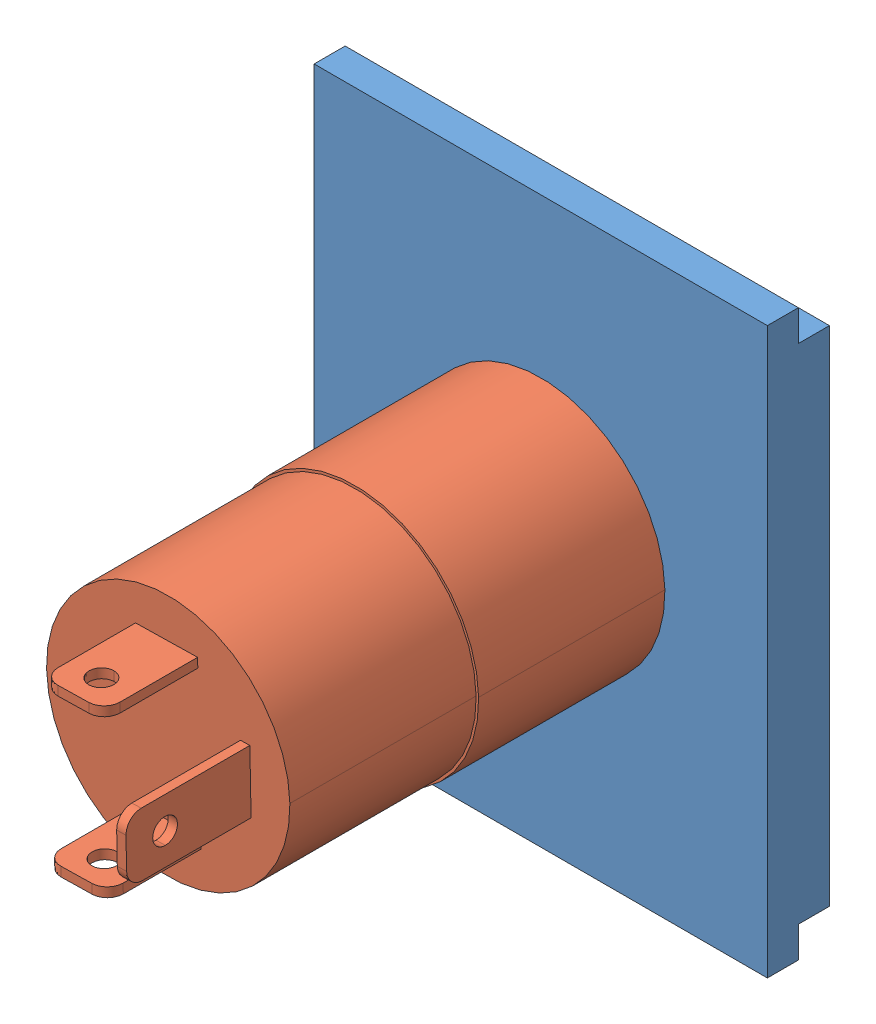
SolidWorks assembly 3,5mm-Klinke-Keystone, configuration Standard. Lengths in mm.
Overall size (14.6 18.2 20.46).
4 component instances, 3 part files, 5 mates.
Components (placement in the parent):
- Keystone-3,5-1: Keystone-3,5 [Standard] at (14.6 -17.2 0) size (14.6 18.2 2)
- 3_5MM Panel Mount Audio Jack - 3 Connector-1: 3_5MM Panel Mount Audio Jack - 3 Connector [Standard] at (3.2208 -5.1808 -2.46) x (-0.9998 -0.020009 0) z (0 0 -1) size (8.44 8.41 20.46)
  - 3.5MM Panel Mount Audio Jack - 4 Connector - korpus-1: 3.5MM Panel Mount Audio Jack - 4 Connector - korpus [Standard] at (-4 -4 -4) size (8 8 20.46)
  - 3.5MM Panel Mount Audio Jack - 4 Connector - nakr_X2_0119_X0_tka-1: 3.5MM Panel Mount Audio Jack - 4 Connector - nakr_X2_0119_X0_tka [Standard] at (-4 -4 -2.46) x (0.998616 0.052592 0) z (0 0 1) size (8.03 8 2.01)
Mates (geometry in assembly coordinates):
- Deckungsgleich1: coincident anti-aligned: plane of Keystone-3,5-1 through (14.6 -17.2 0) normal (0 0 -1); plane of assembly through (0 0 0) normal (0 0 1)
- Deckungsgleich2: coincident aligned: plane of Keystone-3,5-1 through (0 0 2) normal (0 1 0); plane of assembly through (0 0 0) normal (0 1 0)
- Deckungsgleich3: coincident anti-aligned: plane of Keystone-3,5-1 through (0 -17.2 1) normal (-1 0 0); plane of assembly through (0 0 0) normal (1 0 0)
- Konzentrisch1: concentric aligned: cylinder of Keystone-3,5-1 through (7.3 -9.1 10) axis (0 0 -1) radius 3; cylinder of 3_5MM Panel Mount Audio Jack - 3 Connector-1/3.5MM Panel Mount Audio Jack - 4 Connector - korpus-1 through (7.3 -9.1 1.54) axis (0 0 -1) radius 3
- Deckungsgleich4: coincident anti-aligned: plane of Keystone-3,5-1 through (14.6 -17.2 2) normal (0 0 1); plane of 3_5MM Panel Mount Audio Jack - 3 Connector-1/3.5MM Panel Mount Audio Jack - 4 Connector - korpus-1 through (7.3 -9.1 2) normal (0 0 -1)
